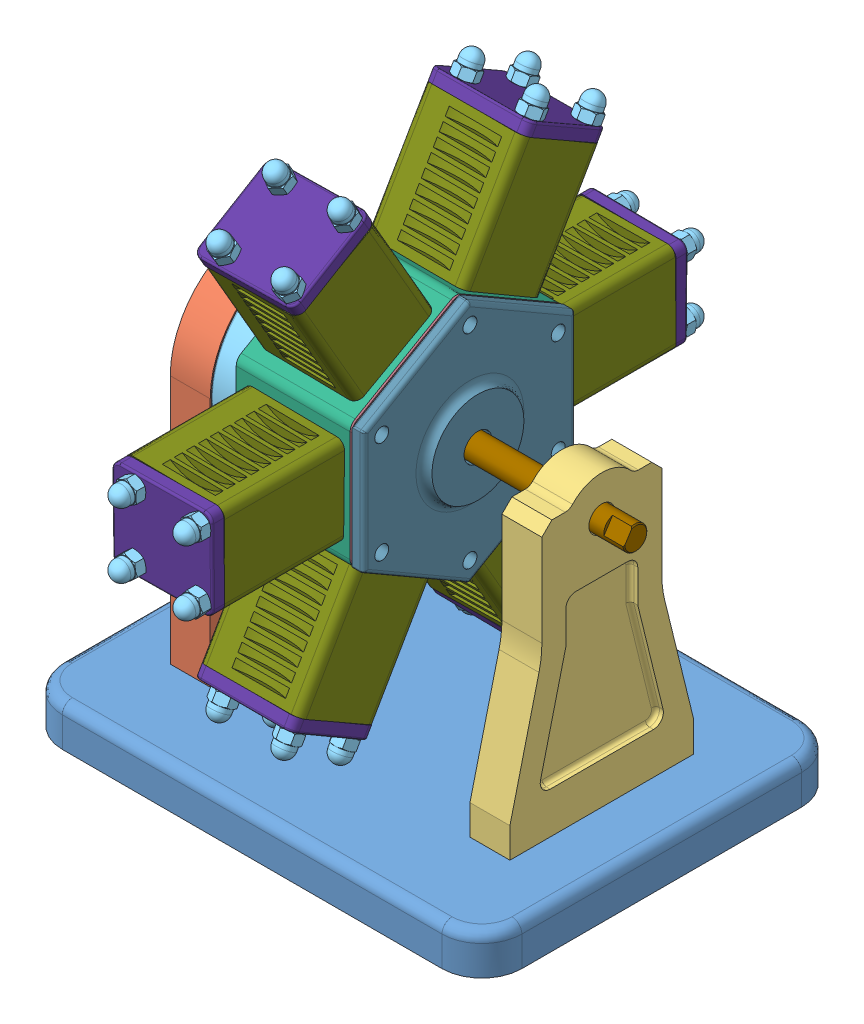
SolidWorks assembly Motor Assembly, configuration Default. Lengths in mm.
Overall size (230 270.19 262).
127 component instances, 25 part files, 104 mates.
Components (placement in the parent):
- 1.Base-1: 1.Base [Default] at (78.8559 86.8104 196.0096) size (230 20 180)
- 2.Pillar Support-1: 2.Pillar Support [Default] at (3.8559 231.8104 196.0096) x (0 0 -1) z (1 0 0) size (92 171 20)
- 3.Bearing Holder-1: 3.Bearing Holder [Default] at (153.8559 231.8104 196.0096) x (0 0 1) z (-1 0 0) size (92 145 20)
- 11.Valve-1: 11.Valve [Default] at (33.8559 233.4481 198.5232) x (0 -0.240272 0.970706) z (-1 0 0) size (42 42 14)
- 12.Valve Housing-1: 12.Valve Housing [Default] at (33.8559 231.8104 196.0096) x (0 0.866025 0.5) z (-1 0 0) size (92 92 30)
- 19.Crankcase-1: 19.Crankcase [Default] at (65.8559 231.8104 196.0096) x (0 0.5 -0.866025) z (1 0 0) size (120.85 106 57)
- Crankshaft Assembly-1: Crankshaft Assembly [Default] at (125.4269 231.5312 143.2681) x (0 -0.837859 0.545886) z (-1 0 0) size (67.26 66 135)
  - 16.Crankshaft Counterweight-1: 16.Crankshaft Counterweight [Default] at (28.5569 44.3424 45.571) size (67.26 66 12)
  - 18.Crankshaft Pin-1: 18.Crankshaft Pin [Default] at (28.5569 62.3424 78.571) size (12 12 38)
  - 16.Crankshaft Counterweight-2: 16.Crankshaft Counterweight [Default] at (28.5569 44.3424 73.571) size (67.26 66 12)
  - 17.Crankshaft-1: 17.Crankshaft [Default] at (28.5569 44.3424 50.571) x (-1 0 0) z (0 0 -1) size (12 12 106)
- 14.Crankshaft Valve-1: 14.Crankshaft Valve [Default] at (56.8559 231.8104 196.0096) x (0 0.837859 -0.545886) z (-1 0 0) size (12 12 33)
- radial ball bearing_68_skf-1: radial ball bearing_68_skf [SKF - 6001 - Full,DE,NC,Full_68] at (153.8559 231.8104 196.0096) x (1 0 0) z (0 -0.041942 0.99912) size (8 28 28)
- radial ball bearing_68_skf-2: radial ball bearing_68_skf [SKF - 6001 - Full,DE,NC,Full_68] at (41.8559 231.8104 196.0096) x (1 0 0) z (0 -0.041942 0.99912) size (8 28 28)
- 15.Connecting Rod Hub-1: 15.Connecting Rod Hub [Default] at (65.8559 241.6363 211.0911) x (0 0.906482 0.422244) z (0 0.422244 -0.906482) size (42 16 42)
- 20.Crankcase Gasket-1: 20.Crankcase Gasket [Default] at (91.8559 231.8104 196.0096) x (0 0 1) z (-1 0 0) size (106 120.85 1)
- 21.Crankcase cover-1: 21.Crankcase cover [Default] at (85.8559 231.8104 196.0096) x (0 0 -1) z (1 0 0) size (106 122.09 16)
- radial ball bearing_68_skf-3: radial ball bearing_68_skf [SKF - 6001 - Full,DE,NC,Full_68] at (89.8559 231.8104 196.0096) x (1 0 0) z (0 0.414709 0.909954) size (8 28 28)
- 22.Hub Pin-1: 22.Hub Pin [Default] at (73.8559 225.6978 212.4921) x (0 0.010581 0.999944) z (-1 0 0) size (5 5 16)
- 22.Hub Pin-2: 22.Hub Pin [Default] at (73.8559 232.4537 197.9884) x (0 -0.14802 0.988984) z (-1 0 0) size (5 5 16)
- 22.Hub Pin-3: 22.Hub Pin [Default] at (73.8559 234.8804 225.5948) x (0 -0.272819 0.962065) z (-1 0 0) size (5 5 16)
- 22.Hub Pin-4: 22.Hub Pin [Default] at (73.8559 250.819 224.1937) x (0 -0.361308 0.932447) z (-1 0 0) size (5 5 16)
- 22.Hub Pin-5: 22.Hub Pin [Default] at (73.8559 257.5749 209.69) x (0 0.989021 0.147773) z (-1 0 0) size (5 5 16)
- 22.Hub Pin-6: 22.Hub Pin [Default] at (73.8559 248.3923 196.5874) x (0 -0.42038 0.907348) z (-1 0 0) size (5 5 16)
- 8.Cylinder-1: 8.Cylinder [Default] at (65.8559 277.7097 169.5096) x (0.99993 0.00593 0.010271) z (0 0.866025 -0.5) size (50 45 62)
- 9.Cylinder Head-1: 9.Cylinder Head [Default] at (65.8559 329.6713 139.5096) x (-0.999937 0.005618 0.00973) z (-0.011235 -0.499968 -0.865971) size (50 8 45)
- 10.Cylinder Bolt-1: 10.Cylinder Bolt [Default] at (82.1193 328.2166 121.57) x (1 0 0) z (0 -0.866025 0.5) size (6 6 82)
- 10.Cylinder Bolt-6: 10.Cylinder Bolt [Default] at (49.5924 328.2166 121.57) x (0.996402 -0.042374 -0.073394) z (0 -0.866025 0.5) size (6 6 82)
- 10.Cylinder Bolt-7: 10.Cylinder Bolt [Default] at (49.5924 344.4801 149.7392) x (0.9776 -0.105236 -0.182274) z (0 -0.866025 0.5) size (6 6 82)
- 10.Cylinder Bolt-8: 10.Cylinder Bolt [Default] at (82.1193 344.4801 149.7392) x (0.928571 -0.185577 -0.321429) z (0 -0.866025 0.5) size (6 6 82)
- 10.Cylinder Bolt-22: 10.Cylinder Bolt [Default] at (82.1193 328.2166 270.4492) x (0.928571 0.185577 -0.321429) z (0 -0.866025 -0.5) size (6 6 82)
- 10.Cylinder Bolt-23: 10.Cylinder Bolt [Default] at (82.1193 215.5469 316.7196) x (0.928571 0.371154 0) z (0 0 -1) size (6 6 82)
- 10.Cylinder Bolt-24: 10.Cylinder Bolt [Default] at (82.1193 119.1407 242.28) x (0.928571 0.185577 0.321429) z (0 0.866025 -0.5) size (6 6 82)
- 10.Cylinder Bolt-25: 10.Cylinder Bolt [Default] at (82.1193 135.4042 121.57) x (0.928571 -0.185577 0.321429) z (0 0.866025 0.5) size (6 6 82)
- 10.Cylinder Bolt-26: 10.Cylinder Bolt [Default] at (82.1193 248.0739 75.2996) x (0.928571 -0.371154 0) z (0 0 1) size (6 6 82)
- 10.Cylinder Bolt-27: 10.Cylinder Bolt [Default] at (49.5924 328.2166 270.4492) x (0.9776 0.105236 -0.182274) z (0 -0.866025 -0.5) size (6 6 82)
- 10.Cylinder Bolt-28: 10.Cylinder Bolt [Default] at (49.5924 215.5469 316.7196) x (0.9776 0.210472 0) z (0 0 -1) size (6 6 82)
- 10.Cylinder Bolt-29: 10.Cylinder Bolt [Default] at (49.5924 119.1407 242.28) x (0.9776 0.105236 0.182274) z (0 0.866025 -0.5) size (6 6 82)
- 10.Cylinder Bolt-30: 10.Cylinder Bolt [Default] at (49.5924 135.4042 121.57) x (0.9776 -0.105236 0.182274) z (0 0.866025 0.5) size (6 6 82)
- 10.Cylinder Bolt-31: 10.Cylinder Bolt [Default] at (49.5924 248.0739 75.2996) x (0.9776 -0.210472 0) z (0 0 1) size (6 6 82)
- 10.Cylinder Bolt-32: 10.Cylinder Bolt [Default] at (49.5924 344.4801 242.28) x (0.996402 0.042374 -0.073394) z (0 -0.866025 -0.5) size (6 6 82)
- 10.Cylinder Bolt-33: 10.Cylinder Bolt [Default] at (49.5924 248.0739 316.7196) x (0.996402 0.084748 0) z (0 0 -1) size (6 6 82)
- 10.Cylinder Bolt-34: 10.Cylinder Bolt [Default] at (49.5924 135.4042 270.4492) x (0.996402 0.042374 0.073394) z (0 0.866025 -0.5) size (6 6 82)
- 10.Cylinder Bolt-35: 10.Cylinder Bolt [Default] at (49.5924 119.1407 149.7392) x (0.996402 -0.042374 0.073394) z (0 0.866025 0.5) size (6 6 82)
- 10.Cylinder Bolt-36: 10.Cylinder Bolt [Default] at (49.5924 215.5469 75.2996) x (0.996402 -0.084748 0) z (0 0 1) size (6 6 82)
- 10.Cylinder Bolt-37: 10.Cylinder Bolt [Default] at (82.1193 344.4801 242.28) x (1 0 0) z (0 -0.866025 -0.5) size (6 6 82)
- 10.Cylinder Bolt-38: 10.Cylinder Bolt [Default] at (82.1193 248.0739 316.7196) x (1 0 0) z (0 0 -1) size (6 6 82)
- 10.Cylinder Bolt-39: 10.Cylinder Bolt [Default] at (82.1193 135.4042 270.4492) x (1 0 0) z (0 0.866025 -0.5) size (6 6 82)
- 10.Cylinder Bolt-40: 10.Cylinder Bolt [Default] at (82.1193 119.1407 149.7392) x (1 0 0) z (0 0.866025 0.5) size (6 6 82)
- 10.Cylinder Bolt-41: 10.Cylinder Bolt [Default] at (82.1193 215.5469 75.2996) size (6 6 82)
- 9.Cylinder Head-5: 9.Cylinder Head [Default] at (65.8559 329.6713 252.5096) x (-0.999937 -0.005618 0.00973) z (-0.011235 0.499968 -0.865971) size (50 8 45)
- 9.Cylinder Head-6: 9.Cylinder Head [Default] at (65.8559 231.8104 309.0096) x (-0.999937 -0.011235 0) z (-0.011235 0.999937 0) size (50 8 45)
- 9.Cylinder Head-7: 9.Cylinder Head [Default] at (65.8559 133.9495 252.5096) x (-0.999937 -0.005618 -0.00973) z (-0.011235 0.499968 0.865971) size (50 8 45)
- 9.Cylinder Head-8: 9.Cylinder Head [Default] at (65.8559 133.9495 139.5096) x (-0.999937 0.005618 -0.00973) z (-0.011235 -0.499968 0.865971) size (50 8 45)
- 9.Cylinder Head-9: 9.Cylinder Head [Default] at (65.8559 231.8104 83.0096) x (-0.999937 0.011235 0) z (-0.011235 -0.999937 0) size (50 8 45)
- 8.Cylinder-5: 8.Cylinder [Default] at (65.8559 277.7097 222.5096) x (0.99993 -0.00593 0.010271) z (0 0.866025 0.5) size (50 45 62)
- 8.Cylinder-6: 8.Cylinder [Default] at (65.8559 231.8104 249.0096) x (0.99993 -0.01186 0) z (0 0 1) size (50 45 62)
- 8.Cylinder-7: 8.Cylinder [Default] at (65.8559 185.9111 222.5096) x (0.99993 -0.00593 -0.010271) z (0 -0.866025 0.5) size (50 45 62)
- 8.Cylinder-8: 8.Cylinder [Default] at (65.8559 185.9111 169.5096) x (0.99993 0.00593 -0.010271) z (0 -0.866025 -0.5) size (50 45 62)
- 8.Cylinder-9: 8.Cylinder [Default] at (65.8559 231.8104 143.0096) x (0.99993 0.01186 0) z (0 0 -1) size (50 45 62)
- Piston Assembly-1: Piston Assembly [Default] at (41.1019 276.0191 173.3163) x (0 -0.5 -0.866025) z (1 0 0) size (35.7 32 35.67)
  - 4.Piston-1: 4.Piston [Default] at (2.4514 23.7914 24.754) size (32 32 32)
  - 5.Piston_Pin-1: 5.Piston_Pin [Default] at (2.4514 23.7914 9.754) size (5 5 30)
  - 7.Piston Compression Ring-1: 7.Piston Compression Ring [Default] at (2.4514 34.0414 24.754) x (0.992378 0 0.12323) z (-0.12323 0 0.992378) size (32 1.5 31.97)
  - 7.Piston Compression Ring-2: 7.Piston Compression Ring [Default] at (2.4514 29.5414 24.754) x (0.99851 0 0.05457) z (-0.05457 0 0.99851) size (32 1.5 31.97)
- 6.Connecting_rod-1: 6.Connecting_rod [Default] at (65.8559 295.3973 159.2977) x (0 -0.783418 0.621495) z (1 0 0) size (70 10 10)
- domed cap nut_din-1: domed cap nut_din [DIN 1587 - M6 --NNU] at (49.5924 326.7357 122.425) x (0 0.866025 -0.5) z (-0.5 0.433013 0.75) size (12 11.55 10)
- domed cap nut_din-6: domed cap nut_din [DIN 1587 - M6 --NNU] at (82.1193 326.7357 122.425) x (0 0.866025 -0.5) z (-0.424807 0.452642 0.783999) size (12 11.55 10)
- domed cap nut_din-7: domed cap nut_din [DIN 1587 - M6 --NNU] at (49.5924 342.9992 150.5942) x (0 0.866025 -0.5) z (-0.306526 0.475931 0.824337) size (12 11.55 10)
- domed cap nut_din-8: domed cap nut_din [DIN 1587 - M6 --NNU] at (82.1193 342.9992 150.5942) x (0 0.866025 -0.5) z (-0.142857 0.494872 0.857143) size (12 11.55 10)
- domed cap nut_din-10: domed cap nut_din [DIN 1587 - M6 --NNU] at (49.5924 326.7357 269.5942) x (0 0.866025 0.5) z (-0.306526 -0.475931 0.824337) size (12 11.55 10)
- domed cap nut_din-11: domed cap nut_din [DIN 1587 - M6 --NNU] at (49.5924 215.5469 315.0096) x (0 0 1) z (-0.306526 -0.951862 0) size (12 11.55 10)
- domed cap nut_din-12: domed cap nut_din [DIN 1587 - M6 --NNU] at (49.5924 120.6216 241.425) x (0 -0.866025 0.5) z (-0.306526 -0.475931 -0.824337) size (12 11.55 10)
- domed cap nut_din-13: domed cap nut_din [DIN 1587 - M6 --NNU] at (49.5924 136.8851 122.425) x (0 -0.866025 -0.5) z (-0.306526 0.475931 -0.824337) size (12 11.55 10)
- domed cap nut_din-14: domed cap nut_din [DIN 1587 - M6 --NNU] at (49.5924 248.0739 77.0096) x (0 0 -1) z (-0.306526 0.951862 0) size (12 11.55 10)
- domed cap nut_din-15: domed cap nut_din [DIN 1587 - M6 --NNU] at (82.1193 326.7357 269.5942) x (0 0.866025 0.5) z (-0.142857 -0.494872 0.857143) size (12 11.55 10)
- domed cap nut_din-16: domed cap nut_din [DIN 1587 - M6 --NNU] at (82.1193 215.5469 315.0096) x (0 0 1) z (-0.142857 -0.989743 0) size (12 11.55 10)
- domed cap nut_din-17: domed cap nut_din [DIN 1587 - M6 --NNU] at (82.1193 120.6216 241.425) x (0 -0.866025 0.5) z (-0.142857 -0.494872 -0.857143) size (12 11.55 10)
- domed cap nut_din-18: domed cap nut_din [DIN 1587 - M6 --NNU] at (82.1193 136.8851 122.425) x (0 -0.866025 -0.5) z (-0.142857 0.494872 -0.857143) size (12 11.55 10)
- domed cap nut_din-19: domed cap nut_din [DIN 1587 - M6 --NNU] at (82.1193 248.0739 77.0096) x (0 0 -1) z (-0.142857 0.989743 0) size (12 11.55 10)
- domed cap nut_din-20: domed cap nut_din [DIN 1587 - M6 --NNU] at (82.1193 342.9992 241.425) x (0 0.866025 0.5) z (-0.424807 -0.452642 0.783999) size (12 11.55 10)
- domed cap nut_din-21: domed cap nut_din [DIN 1587 - M6 --NNU] at (82.1193 248.0739 315.0096) x (0 0 1) z (-0.424807 -0.905284 0) size (12 11.55 10)
- domed cap nut_din-22: domed cap nut_din [DIN 1587 - M6 --NNU] at (82.1193 136.8851 269.5942) x (0 -0.866025 0.5) z (-0.424807 -0.452642 -0.783999) size (12 11.55 10)
- domed cap nut_din-23: domed cap nut_din [DIN 1587 - M6 --NNU] at (82.1193 120.6216 150.5942) x (0 -0.866025 -0.5) z (-0.424807 0.452642 -0.783999) size (12 11.55 10)
- domed cap nut_din-24: domed cap nut_din [DIN 1587 - M6 --NNU] at (82.1193 215.5469 77.0096) x (0 0 -1) z (-0.424807 0.905284 0) size (12 11.55 10)
- domed cap nut_din-25: domed cap nut_din [DIN 1587 - M6 --NNU] at (49.5924 342.9992 241.425) x (0 0.866025 0.5) z (-0.5 -0.433013 0.75) size (12 11.55 10)
- domed cap nut_din-26: domed cap nut_din [DIN 1587 - M6 --NNU] at (49.5924 248.0739 315.0096) x (0 0 1) z (-0.5 -0.866025 0) size (12 11.55 10)
- domed cap nut_din-27: domed cap nut_din [DIN 1587 - M6 --NNU] at (49.5924 136.8851 269.5942) x (0 -0.866025 0.5) z (-0.5 -0.433013 -0.75) size (12 11.55 10)
- domed cap nut_din-28: domed cap nut_din [DIN 1587 - M6 --NNU] at (49.5924 120.6216 150.5942) x (0 -0.866025 -0.5) z (-0.5 0.433013 -0.75) size (12 11.55 10)
- domed cap nut_din-29: domed cap nut_din [DIN 1587 - M6 --NNU] at (49.5924 215.5469 77.0096) x (0 0 -1) z (-0.5 0.866025 0) size (12 11.55 10)
- Piston Assembly-4: Piston Assembly [Default] at (41.1019 287.1817 230.8088) x (0 0.5 -0.866025) z (1 0 0) size (35.7 32 35.67)
  - 4.Piston-1: 4.Piston [Default] at (2.4514 23.7914 24.754) size (32 32 32)
  - 5.Piston_Pin-1: 5.Piston_Pin [Default] at (2.4514 23.7914 9.754) size (5 5 30)
  - 7.Piston Compression Ring-1: 7.Piston Compression Ring [Default] at (2.4514 34.0414 24.754) x (0.992378 0 0.12323) z (-0.12323 0 0.992378) size (32 1.5 31.97)
  - 7.Piston Compression Ring-2: 7.Piston Compression Ring [Default] at (2.4514 29.5414 24.754) x (0.99851 0 0.05457) z (-0.05457 0 0.99851) size (32 1.5 31.97)
- 6.Connecting_rod-4: 6.Connecting_rod [Default] at (65.8559 309.0114 240.5816) x (0 -0.857274 -0.51486) z (1 0 0) size (70 10 10)
- Piston Assembly-6: Piston Assembly [Default] at (41.1019 229.359 114.2005) x (0 1 0) z (1 0 0) size (35.7 32 35.67)
  - 4.Piston-1: 4.Piston [Default] at (2.4514 23.7914 24.754) size (32 32 32)
  - 5.Piston_Pin-1: 5.Piston_Pin [Default] at (2.4514 23.7914 9.754) size (5 5 30)
  - 7.Piston Compression Ring-1: 7.Piston Compression Ring [Default] at (2.4514 34.0414 24.754) x (0.992378 0 0.12323) z (-0.12323 0 0.992378) size (32 1.5 31.97)
  - 7.Piston Compression Ring-2: 7.Piston Compression Ring [Default] at (2.4514 29.5414 24.754) x (0.99851 0 0.05457) z (-0.05457 0 0.99851) size (32 1.5 31.97)
- 6.Connecting_rod-6: 6.Connecting_rod [Default] at (65.8559 231.8104 137.9919) x (0 0.010722 0.999943) z (1 0 0) size (70 10 10)
- Piston Assembly-8: Piston Assembly [Default] at (41.1019 162.7867 158.9894) x (0 0.5 -0.866025) z (1 0 0) size (35.7 32 35.67)
  - 4.Piston-1: 4.Piston [Default] at (2.4514 23.7914 24.754) size (32 32 32)
  - 5.Piston_Pin-1: 5.Piston_Pin [Default] at (2.4514 23.7914 9.754) size (5 5 30)
  - 7.Piston Compression Ring-1: 7.Piston Compression Ring [Default] at (2.4514 34.0414 24.754) x (0.992378 0 0.12323) z (-0.12323 0 0.992378) size (32 1.5 31.97)
  - 7.Piston Compression Ring-2: 7.Piston Compression Ring [Default] at (2.4514 29.5414 24.754) x (0.99851 0 0.05457) z (-0.05457 0 0.99851) size (32 1.5 31.97)
- 6.Connecting_rod-8: 6.Connecting_rod [Default] at (65.8559 184.6164 168.7621) x (0 0.684691 0.728834) z (1 0 0) size (70 10 10)
- Piston Assembly-10: Piston Assembly [Default] at (41.1019 194.3459 214.8092) x (0 0.5 0.866025) z (1 0 0) size (35.7 32 35.67)
  - 4.Piston-1: 4.Piston [Default] at (2.4514 23.7914 24.754) size (32 32 32)
  - 5.Piston_Pin-1: 5.Piston_Pin [Default] at (2.4514 23.7914 9.754) size (5 5 30)
  - 7.Piston Compression Ring-1: 7.Piston Compression Ring [Default] at (2.4514 34.0414 24.754) x (0.992378 0 0.12323) z (-0.12323 0 0.992378) size (32 1.5 31.97)
  - 7.Piston Compression Ring-2: 7.Piston Compression Ring [Default] at (2.4514 29.5414 24.754) x (0.99851 0 0.05457) z (-0.05457 0 0.99851) size (32 1.5 31.97)
- 6.Connecting_rod-10: 6.Connecting_rod [Default] at (65.8559 174.9676 228.8278) x (0 0.998547 -0.053884) z (1 0 0) size (70 10 10)
- Piston Assembly-13: Piston Assembly [Default] at (90.6099 234.2618 257.3117) x (0 -1 0) z (-1 0 0) size (35.7 32 35.67)
  - 4.Piston-1: 4.Piston [Default] at (2.4514 23.7914 24.754) size (32 32 32)
  - 5.Piston_Pin-1: 5.Piston_Pin [Default] at (2.4514 23.7914 9.754) size (5 5 30)
  - 7.Piston Compression Ring-1: 7.Piston Compression Ring [Default] at (2.4514 34.0414 24.754) x (0.992378 0 0.12323) z (-0.12323 0 0.992378) size (32 1.5 31.97)
  - 7.Piston Compression Ring-2: 7.Piston Compression Ring [Default] at (2.4514 29.5414 24.754) x (0.99851 0 0.05457) z (-0.05457 0 0.99851) size (32 1.5 31.97)
- 6.Connecting_rod-13: 6.Connecting_rod [Default] at (65.8559 231.8104 281.1031) x (0 0.31681 -0.948489) z (-1 0 0) size (70 10 10)
- socket head cap screw_iso-2: socket head cap screw_iso [ISO 4762 M6 x 45 - 45N] at (-6.1441 270.8104 196.0096) size (51 10 10)
- socket head cap screw_iso-3: socket head cap screw_iso [ISO 4762 M6 x 45 - 45N] at (-6.1441 251.3104 229.7846) size (51 10 10)
- socket head cap screw_iso-4: socket head cap screw_iso [ISO 4762 M6 x 45 - 45N] at (-6.1441 212.3104 229.7846) size (51 10 10)
- socket head cap screw_iso-5: socket head cap screw_iso [ISO 4762 M6 x 45 - 45N] at (-6.1441 192.8104 196.0096) size (51 10 10)
- socket head cap screw_iso-6: socket head cap screw_iso [ISO 4762 M6 x 45 - 45N] at (-6.1441 212.3104 162.2346) size (51 10 10)
- socket head cap screw_iso-7: socket head cap screw_iso [ISO 4762 M6 x 45 - 45N] at (-6.1441 251.3104 162.2346) size (51 10 10)
- 13.Flywheel-1: 13.Flywheel [Default] at (125.8559 231.8104 196.0096) x (0 -0.945721 0.324979) z (-1 0 0) size (160 160 36) (hidden)
Mates (geometry in assembly coordinates):
- Coincident1: coincident anti-aligned: plane of 1.Base-1 through (-16.1441 106.8104 266.0096) normal (0 1 0); plane of 2.Pillar Support-1 through (13.8559 106.8104 242.0096) normal (0 -1 0)
- Concentric3: concentric anti-aligned: circle of 1.Base-1; circle of 2.Pillar Support-1
- Concentric4: concentric anti-aligned: circle of 1.Base-1; circle of 2.Pillar Support-1
- Concentric5: concentric anti-aligned: circle of 1.Base-1; circle of 3.Bearing Holder-1
- Concentric6: concentric aligned: circle of 1.Base-1; circle of 3.Bearing Holder-1
- Coincident2: coincident anti-aligned: plane of 1.Base-1 through (-16.1441 106.8104 266.0096) normal (0 1 0); plane of 3.Bearing Holder-1 through (143.8559 106.8104 150.0096) normal (0 -1 0)
- Concentric7: concentric aligned: cylinder of 2.Pillar Support-1 through (3.8559 231.8104 196.0096) axis (1 0 0) radius 12.5; cylinder of 12.Valve Housing-1 through (3.8559 231.8104 196.0096) axis (1 0 0) radius 12
- Coincident3: coincident anti-aligned: circle of 2.Pillar Support-1; circle of 12.Valve Housing-1
- Coincident4: coincident anti-aligned: plane of 11.Valve-1 through (19.8559 234.2246 197.7905) normal (-1 0 0); plane of 12.Valve Housing-1 through (19.8559 231.8104 196.0096) normal (1 0 0)
- Parallel1: parallel aligned: plane of 1.Base-1 through (-16.1441 106.8104 286.0096) normal (0 0 1); plane of 19.Crankcase-1 through (33.8559 259.5232 249.0096) normal (0 0 1)
- Concentric11: concentric aligned: circle of 3.Bearing Holder-1; circle of 19.Crankcase-1
- Concentric12: concentric anti-aligned: cylinder of 3.Bearing Holder-1 through (143.8559 231.8104 196.0096) axis (1 0 0) radius 6.5; cylinder of Crankshaft Assembly-1/17.Crankshaft-1 through (180.8559 231.8104 196.0096) axis (-1 0 0) radius 6
- Concentric13: concentric aligned: cylinder of Crankshaft Assembly-1/16.Crankshaft Counterweight-2 through (46.8559 231.8104 196.0096) axis (1 0 0) radius 6; cylinder of 14.Crankshaft Valve-1 through (33.8559 231.8104 196.0096) axis (1 0 0) radius 6
- Concentric14: concentric aligned: cylinder of Crankshaft Assembly-1/16.Crankshaft Counterweight-2 through (51.8559 211.8456 223.0746) axis (0 0.593626 -0.804741) radius 1.5; cylinder of 14.Crankshaft Valve-1 through (51.8559 228.2486 200.838) axis (0 0.593626 -0.804741) radius 1.5
- Concentric16: concentric aligned: cylinder of 11.Valve-1 through (19.8559 234.2246 197.7905) axis (1 0 0) radius 2; cylinder of 14.Crankshaft Valve-1 through (23.8559 234.2246 197.7905) axis (1 0 0) radius 2
- Coincident7: coincident anti-aligned: plane of 11.Valve-1 through (33.8559 234.2246 197.7905) normal (1 0 0); plane of 14.Crankshaft Valve-1 through (33.8559 231.8104 196.0096) normal (-1 0 0)
- Coincident9: coincident anti-aligned: plane of 12.Valve Housing-1 through (33.8559 231.8104 196.0096) normal (1 0 0); plane of 19.Crankcase-1 through (33.8559 204.0976 244.0096) normal (-1 0 0)
- Concentric17: concentric anti-aligned: cylinder of Crankshaft Assembly-1/17.Crankshaft-1 through (180.8559 231.8104 196.0096) axis (-1 0 0) radius 6; cylinder of radial ball bearing_68_skf-1 through (133.2184 231.8104 196.0096) axis (1 0 0) radius 6
- Concentric18: concentric anti-aligned: cylinder of 3.Bearing Holder-1 through (157.8559 231.8104 196.0096) axis (-1 0 0) radius 14; cylinder of radial ball bearing_68_skf-1 through (133.2184 231.8104 196.0096) axis (1 0 0) radius 14
- Coincident10: coincident anti-aligned: plane of 3.Bearing Holder-1 through (157.8559 231.8104 196.0096) normal (-1 0 0); plane of radial ball bearing_68_skf-1 through (157.8559 245.4983 196.5842) normal (1 0 0)
- Concentric19: concentric anti-aligned: cylinder of Crankshaft Assembly-1/17.Crankshaft-1 through (180.8559 231.8104 196.0096) axis (-1 0 0) radius 6; cylinder of radial ball bearing_68_skf-2 through (21.2184 231.8104 196.0096) axis (1 0 0) radius 6
- Coincident11: coincident anti-aligned: plane of 19.Crankcase-1 through (37.8559 231.8104 196.0096) normal (1 0 0); plane of radial ball bearing_68_skf-2 through (37.8559 243.4002 196.4961) normal (-1 0 0)
- Concentric20: concentric anti-aligned: cylinder of Crankshaft Assembly-1/18.Crankshaft Pin-1 through (84.8559 246.2957 206.6949) axis (-1 0 0) radius 6; cylinder of 15.Connecting Rod Hub-1 through (105.541 246.2957 206.6949) axis (1 0 0) radius 6
- Coincident13: coincident anti-aligned: plane of Crankshaft Assembly-1/16.Crankshaft Counterweight-2 through (57.8559 246.2957 206.6949) normal (1 0 0); plane of 15.Connecting Rod Hub-1 through (57.8559 240.8568 204.1614) normal (-1 0 0)
- Coincident14: coincident anti-aligned: plane of 19.Crankcase-1 through (90.8559 204.0976 244.0096) normal (1 0 0); plane of 20.Crankcase Gasket-1 through (90.8559 204.0976 148.0096) normal (-1 0 0)
- Concentric21: concentric anti-aligned: circle of 19.Crankcase-1; circle of 20.Crankcase Gasket-1
- Concentric22: concentric anti-aligned: cylinder of 21.Crankcase cover-1 through (91.8559 231.8104 196.0096) axis (-1 0 0) radius 14; cylinder of radial ball bearing_68_skf-3 through (69.2184 231.8104 196.0096) axis (1 0 0) radius 14
- Concentric23: concentric anti-aligned: cylinder of Crankshaft Assembly-1/17.Crankshaft-1 through (180.8559 231.8104 196.0096) axis (-1 0 0) radius 6; cylinder of radial ball bearing_68_skf-3 through (69.2184 231.8104 196.0096) axis (1 0 0) radius 6
- Coincident16: coincident anti-aligned: plane of 20.Crankcase Gasket-1 through (91.8559 204.0976 148.0096) normal (1 0 0); plane of 21.Crankcase cover-1 through (91.8559 231.8104 196.0096) normal (-1 0 0)
- Concentric24: concentric anti-aligned: cylinder of 15.Connecting Rod Hub-1 through (73.8559 230.3572 208.0959) axis (-1 0 0) radius 2.5; cylinder of 22.Hub Pin-1 through (57.8559 230.3572 208.0959) axis (1 0 0) radius 2.5
- Coincident17: coincident aligned: plane of 15.Connecting Rod Hub-1 through (73.8559 227.2596 197.8277) normal (1 0 0); plane of 22.Hub Pin-1 through (73.8559 230.3572 208.0959) normal (1 0 0)
- Coincident18: coincident aligned: plane of 15.Connecting Rod Hub-1 through (73.8559 227.2596 197.8277) normal (1 0 0); plane of 22.Hub Pin-2 through (73.8559 237.1131 193.5922) normal (1 0 0)
- Concentric27: concentric anti-aligned: cylinder of 15.Connecting Rod Hub-1 through (73.8559 237.1131 193.5922) axis (-1 0 0) radius 2.5; cylinder of 22.Hub Pin-2 through (57.8559 237.1131 193.5922) axis (1 0 0) radius 2.5
- Coincident19: coincident aligned: plane of 15.Connecting Rod Hub-1 through (73.8559 227.2596 197.8277) normal (1 0 0); plane of 22.Hub Pin-3 through (73.8559 239.5398 221.1986) normal (1 0 0)
- Concentric28: concentric anti-aligned: cylinder of 15.Connecting Rod Hub-1 through (73.8559 239.5398 221.1986) axis (-1 0 0) radius 2.5; cylinder of 22.Hub Pin-3 through (57.8559 239.5398 221.1986) axis (1 0 0) radius 2.5
- Coincident20: coincident aligned: plane of 15.Connecting Rod Hub-1 through (73.8559 227.2596 197.8277) normal (1 0 0); plane of 22.Hub Pin-4 through (73.8559 255.4784 219.7975) normal (1 0 0)
- Concentric29: concentric anti-aligned: cylinder of 15.Connecting Rod Hub-1 through (73.8559 255.4784 219.7975) axis (-1 0 0) radius 2.5; cylinder of 22.Hub Pin-4 through (57.8559 255.4784 219.7975) axis (1 0 0) radius 2.5
- Coincident21: coincident aligned: plane of 15.Connecting Rod Hub-1 through (73.8559 227.2596 197.8277) normal (1 0 0); plane of 22.Hub Pin-5 through (73.8559 262.2343 205.2938) normal (1 0 0)
- Concentric30: concentric anti-aligned: cylinder of 15.Connecting Rod Hub-1 through (73.8559 262.2343 205.2938) axis (-1 0 0) radius 2.5; cylinder of 22.Hub Pin-5 through (57.8559 262.2343 205.2938) axis (1 0 0) radius 2.5
- Coincident22: coincident aligned: plane of 15.Connecting Rod Hub-1 through (73.8559 227.2596 197.8277) normal (1 0 0); plane of 22.Hub Pin-6 through (73.8559 253.0516 192.1912) normal (1 0 0)
- Concentric31: concentric anti-aligned: cylinder of 15.Connecting Rod Hub-1 through (73.8559 253.0516 192.1912) axis (-1 0 0) radius 2.5; cylinder of 22.Hub Pin-6 through (57.8559 253.0516 192.1912) axis (1 0 0) radius 2.5
- Concentric32: concentric anti-aligned: circle of 19.Crankcase-1; circle of 8.Cylinder-1
- Concentric33: concentric aligned: circle of 19.Crankcase-1; circle of 8.Cylinder-1
- Coincident25: coincident anti-aligned: plane of 19.Crankcase-1 through (33.8559 263.8533 145.5096) normal (0 0.866025 -0.5); plane of 8.Cylinder-1 through (41.6382 286.8168 185.2835) normal (0 -0.866025 0.5)
- Concentric34: concentric anti-aligned: cylinder of 8.Cylinder-1 through (65.8559 329.6713 139.5096) axis (0 -0.866025 0.5) radius 16; cylinder of 9.Cylinder Head-1 through (65.8559 327.9392 140.5096) axis (0 0.866025 -0.5) radius 16
- Concentric35: concentric aligned: circle of 8.Cylinder-1; circle of 9.Cylinder Head-1
- Concentric36: concentric anti-aligned: cylinder of 8.Cylinder-1 through (82.1193 321.5395 125.425) axis (0 -0.866025 0.5) radius 3.5; cylinder of 10.Cylinder Bolt-1 through (82.1193 257.2025 162.57) axis (0 0.866025 -0.5) radius 3
- Distance1: distance = 7.71 mm aligned: plane of 10.Cylinder Bolt-1 through (82.1193 328.2166 121.57) normal (0 0.866025 -0.5); plane of 8.Cylinder-1 through (41.6382 338.7783 155.2835) normal (0 0.866025 -0.5)
- Concentric40: concentric anti-aligned: cylinder of 8.Cylinder-1 through (49.5924 321.5395 125.425) axis (0 -0.866025 0.5) radius 3.5; cylinder of 10.Cylinder Bolt-6 through (49.5924 257.2025 162.57) axis (0 0.866025 -0.5) radius 3
- Distance6: distance = 7.71 mm aligned: plane of 10.Cylinder Bolt-6 through (49.5924 328.2166 121.57) normal (0 0.866025 -0.5); plane of 8.Cylinder-1 through (41.6382 338.7783 155.2835) normal (0 0.866025 -0.5)
- Distance7: distance = 7.71 mm aligned: plane of 10.Cylinder Bolt-7 through (49.5924 344.4801 149.7392) normal (0 0.866025 -0.5); plane of 8.Cylinder-1 through (41.6382 338.7783 155.2835) normal (0 0.866025 -0.5)
- Concentric41: concentric anti-aligned: cylinder of 8.Cylinder-1 through (49.5924 337.803 153.5942) axis (0 -0.866025 0.5) radius 3.5; cylinder of 10.Cylinder Bolt-7 through (49.5924 273.466 190.7392) axis (0 0.866025 -0.5) radius 3
- Distance8: distance = 7.71 mm aligned: plane of 10.Cylinder Bolt-8 through (82.1193 344.4801 149.7392) normal (0 0.866025 -0.5); plane of 8.Cylinder-1 through (41.6382 338.7783 155.2835) normal (0 0.866025 -0.5)
- Concentric42: concentric anti-aligned: cylinder of 8.Cylinder-1 through (82.1193 337.803 153.5942) axis (0 -0.866025 0.5) radius 3.5; cylinder of 10.Cylinder Bolt-8 through (82.1193 273.466 190.7392) axis (0 0.866025 -0.5) radius 3
- Coincident27: coincident anti-aligned: plane of 8.Cylinder-1 through (41.6382 338.7783 155.2835) normal (0 0.866025 -0.5); plane of 9.Cylinder Head-1 through (65.8559 329.6713 139.5096) normal (0 -0.866025 0.5)
- Concentric65: concentric aligned: circle of Piston Assembly-1/5.Piston_Pin-1; circle of 6.Connecting_rod-1
- Symmetric1: symmetric aligned: plane of Piston Assembly-1 through (65.8559 281.5905 170.0996) normal (1 0 0); plane of 6.Connecting_rod-1 through (70.8559 300.9688 156.081) normal (1 0 0); plane of 6.Connecting_rod-1 through (60.8559 300.9688 156.081) normal (-1 0 0)
- Coincident33: coincident anti-aligned: plane of Crankshaft Assembly-1/16.Crankshaft Counterweight-1 through (85.8559 246.2957 206.6949) normal (1 0 0); plane of radial ball bearing_68_skf-3 through (85.8559 242.3659 191.199) normal (-1 0 0)
- Concentric68: concentric anti-aligned: cylinder of 8.Cylinder-1 through (65.8559 329.6713 139.5096) axis (0 -0.866025 0.5) radius 16; cylinder of Piston Assembly-1/4.Piston-1 through (65.8559 314.8252 148.081) axis (0 0.866025 -0.5) radius 16
- Concentric69: concentric anti-aligned: cylinder of 22.Hub Pin-6 through (57.8559 253.0516 192.1912) axis (1 0 0) radius 2.5; cylinder of 6.Connecting_rod-1 through (70.8559 253.0516 192.1912) axis (-1 0 0) radius 2.5
- RackPinionMate1: rack pinion = 12 mm: cylinder of Crankshaft Assembly-1/17.Crankshaft-1 through (180.8559 231.8104 196.0096) axis (-1 0 0) radius 6; cylinder of 15.Connecting Rod Hub-1 through (105.541 246.2957 206.6949) axis (1 0 0) radius 6
- Coincident39: coincident anti-aligned: plane of 9.Cylinder Head-1 through (65.8559 334.8674 136.5096) normal (0 0.866025 -0.5); plane of domed cap nut_din-1 through (44.5924 331.0658 129.925) normal (0 -0.866025 0.5)
- Concentric74: concentric anti-aligned: circle of 10.Cylinder Bolt-6; circle of domed cap nut_din-1
- Coincident40: coincident anti-aligned: plane of 9.Cylinder Head-1 through (65.8559 334.8674 136.5096) normal (0 0.866025 -0.5); plane of domed cap nut_din-6 through (77.8713 331.2621 130.265) normal (0 -0.866025 0.5)
- Concentric75: concentric anti-aligned: circle of 10.Cylinder Bolt-1; circle of domed cap nut_din-6
- Coincident41: coincident anti-aligned: plane of 9.Cylinder Head-1 through (65.8559 334.8674 136.5096) normal (0 0.866025 -0.5); plane of domed cap nut_din-7 through (46.5272 347.7585 158.8375) normal (0 -0.866025 0.5)
- Concentric76: concentric anti-aligned: circle of 10.Cylinder Bolt-7; circle of domed cap nut_din-7
- Coincident42: coincident anti-aligned: plane of 9.Cylinder Head-1 through (65.8559 334.8674 136.5096) normal (0 0.866025 -0.5); plane of domed cap nut_din-8 through (80.6908 347.9479 159.1656) normal (0 -0.866025 0.5)
- Concentric77: concentric anti-aligned: circle of 10.Cylinder Bolt-8; circle of domed cap nut_din-8
- Concentric83: concentric aligned: circle of Piston Assembly-4/5.Piston_Pin-1; circle of 6.Connecting_rod-4
- Symmetric4: symmetric aligned: plane of Piston Assembly-4 through (65.8559 288.4079 231.5168) normal (1 0 0); plane of 6.Connecting_rod-4 through (70.8559 310.2375 241.2895) normal (1 0 0); plane of 6.Connecting_rod-4 through (60.8559 310.2375 241.2895) normal (-1 0 0)
- Concentric84: concentric anti-aligned: cylinder of 8.Cylinder-5 through (65.8559 329.6713 252.5096) axis (0 -0.866025 -0.5) radius 16; cylinder of Piston Assembly-4/4.Piston-1 through (65.8559 324.0939 249.2895) axis (0 0.866025 0.5) radius 16
- Concentric85: concentric anti-aligned: cylinder of 22.Hub Pin-5 through (57.8559 262.2343 205.2938) axis (1 0 0) radius 2.5; cylinder of 6.Connecting_rod-4 through (70.8559 262.2343 205.2938) axis (-1 0 0) radius 2.5
- Concentric87: concentric aligned: circle of Piston Assembly-6/5.Piston_Pin-1; circle of 6.Connecting_rod-6
- Symmetric6: symmetric aligned: plane of Piston Assembly-6 through (65.8559 229.359 110.0356) normal (1 0 0); plane of 6.Connecting_rod-6 through (70.8559 231.8104 133.827) normal (1 0 0); plane of 6.Connecting_rod-6 through (60.8559 231.8104 133.827) normal (-1 0 0)
- Concentric88: concentric anti-aligned: cylinder of 8.Cylinder-6 through (65.8559 231.8104 309.0096) axis (0 0 -1) radius 16; cylinder of Piston Assembly-6/4.Piston-1 through (65.8559 231.8104 149.827) axis (0 0 1) radius 16
- Concentric90: concentric anti-aligned: cylinder of 22.Hub Pin-2 through (57.8559 237.1131 193.5922) axis (1 0 0) radius 2.5; cylinder of 6.Connecting_rod-6 through (70.8559 237.1131 193.5922) axis (-1 0 0) radius 2.5
- Concentric92: concentric aligned: circle of Piston Assembly-8/5.Piston_Pin-1; circle of 6.Connecting_rod-8
- Symmetric8: symmetric aligned: plane of Piston Assembly-8 through (65.8559 163.0751 159.1559) normal (1 0 0); plane of 6.Connecting_rod-8 through (70.8559 184.9048 168.9286) normal (1 0 0); plane of 6.Connecting_rod-8 through (60.8559 184.9048 168.9286) normal (-1 0 0)
- Concentric94: concentric anti-aligned: cylinder of 22.Hub Pin-1 through (57.8559 230.3572 208.0959) axis (1 0 0) radius 2.5; cylinder of 6.Connecting_rod-8 through (70.8559 230.3572 208.0959) axis (-1 0 0) radius 2.5
- Concentric96: concentric aligned: circle of 8.Cylinder-8; cylinder of Piston Assembly-8/4.Piston-1 through (65.8559 198.7612 176.9286) axis (0 0.866025 0.5) radius 16
- Concentric98: concentric aligned: circle of Piston Assembly-10/5.Piston_Pin-1; circle of 6.Connecting_rod-10
- Symmetric10: symmetric aligned: plane of Piston Assembly-10 through (65.8559 199.1165 212.0549) normal (1 0 0); plane of 6.Connecting_rod-10 through (70.8559 179.7382 226.0735) normal (1 0 0); plane of 6.Connecting_rod-10 through (60.8559 179.7382 226.0735) normal (-1 0 0)
- Concentric99: concentric anti-aligned: cylinder of 8.Cylinder-7 through (65.8559 133.9495 252.5096) axis (0 0.866025 -0.5) radius 16; cylinder of Piston Assembly-10/4.Piston-1 through (65.8559 165.8818 234.0735) axis (0 -0.866025 0.5) radius 16
- Concentric100: concentric anti-aligned: cylinder of 22.Hub Pin-3 through (57.8559 239.5398 221.1986) axis (1 0 0) radius 2.5; cylinder of 6.Connecting_rod-10 through (70.8559 239.5398 221.1986) axis (-1 0 0) radius 2.5
- Concentric105: concentric aligned: circle of Piston Assembly-13/5.Piston_Pin-1; circle of 6.Connecting_rod-13
- Symmetric13: symmetric aligned: plane of Piston Assembly-13 through (65.8559 234.2618 251.1408) normal (-1 0 0); plane of 6.Connecting_rod-13 through (60.8559 231.8104 274.9322) normal (-1 0 0); plane of 6.Connecting_rod-13 through (70.8559 231.8104 274.9322) normal (1 0 0)
- Concentric106: concentric anti-aligned: cylinder of 8.Cylinder-6 through (65.8559 231.8104 309.0096) axis (0 0 -1) radius 16; cylinder of Piston Assembly-13/4.Piston-1 through (65.8559 231.8104 290.9322) axis (0 0 1) radius 16
- Concentric109: concentric anti-aligned: cylinder of 2.Pillar Support-1 through (-6.1441 270.8104 196.0096) axis (1 0 0) radius 3.5; cylinder of socket head cap screw_iso-2 through (-37.8941 270.8104 196.0096) axis (-1 0 0) radius 5
- Coincident44: coincident anti-aligned: plane of 2.Pillar Support-1 through (-0.1441 270.8104 196.0096) normal (-1 0 0); plane of socket head cap screw_iso-2 through (-0.1441 275.8104 196.0096) normal (1 0 0)
- Concentric110: concentric aligned: cylinder of 2.Pillar Support-1 through (-0.1441 251.3104 229.7846) axis (-1 0 0) radius 6; cylinder of socket head cap screw_iso-3 through (-37.8941 251.3104 229.7846) axis (-1 0 0) radius 5
- Coincident45: coincident anti-aligned: plane of 2.Pillar Support-1 through (-0.1441 251.3104 229.7846) normal (-1 0 0); plane of socket head cap screw_iso-3 through (-0.1441 256.3104 229.7846) normal (1 0 0)
- Concentric111: concentric aligned: cylinder of 2.Pillar Support-1 through (-0.1441 212.3104 229.7846) axis (-1 0 0) radius 6; cylinder of socket head cap screw_iso-4 through (-37.8941 212.3104 229.7846) axis (-1 0 0) radius 5
- Coincident46: coincident anti-aligned: plane of 2.Pillar Support-1 through (-0.1441 212.3104 229.7846) normal (-1 0 0); plane of socket head cap screw_iso-4 through (-0.1441 217.3104 229.7846) normal (1 0 0)
- Concentric112: concentric anti-aligned: cylinder of 2.Pillar Support-1 through (-6.1441 192.8104 196.0096) axis (1 0 0) radius 3.5; cylinder of socket head cap screw_iso-5 through (-37.8941 192.8104 196.0096) axis (-1 0 0) radius 5
- Coincident47: coincident anti-aligned: plane of 2.Pillar Support-1 through (-0.1441 192.8104 196.0096) normal (-1 0 0); plane of socket head cap screw_iso-5 through (-0.1441 197.8104 196.0096) normal (1 0 0)
- Concentric113: concentric anti-aligned: cylinder of 2.Pillar Support-1 through (-6.1441 212.3104 162.2346) axis (1 0 0) radius 3.5; cylinder of socket head cap screw_iso-6 through (-37.8941 212.3104 162.2346) axis (-1 0 0) radius 5
- Coincident48: coincident anti-aligned: plane of 2.Pillar Support-1 through (-0.1441 212.3104 162.2346) normal (-1 0 0); plane of socket head cap screw_iso-6 through (-0.1441 217.3104 162.2346) normal (1 0 0)
- Concentric114: concentric anti-aligned: cylinder of 2.Pillar Support-1 through (-6.1441 251.3104 162.2346) axis (1 0 0) radius 3.5; cylinder of socket head cap screw_iso-7 through (-37.8941 251.3104 162.2346) axis (-1 0 0) radius 5
- Coincident49: coincident anti-aligned: plane of 2.Pillar Support-1 through (-0.1441 251.3104 162.2346) normal (-1 0 0); plane of socket head cap screw_iso-7 through (-0.1441 256.3104 162.2346) normal (1 0 0)
- Concentric115: concentric anti-aligned: cylinder of Crankshaft Assembly-1/17.Crankshaft-1 through (180.8559 231.8104 196.0096) axis (-1 0 0) radius 6; cylinder of 13.Flywheel-1 through (107.8559 231.8104 196.0096) axis (1 0 0) radius 6
- Coincident50: coincident anti-aligned: plane of 3.Bearing Holder-1 through (143.8559 248.8104 214.3399) normal (-1 0 0); plane of 13.Flywheel-1 through (143.8559 231.8104 196.0096) normal (1 0 0)
- Concentric116: concentric anti-aligned: cylinder of Crankshaft Assembly-1/17.Crankshaft-1 through (180.8559 231.8104 196.0096) axis (-1 0 0) radius 6; cylinder of 13.Flywheel-1 through (107.8559 231.8104 196.0096) axis (1 0 0) radius 80
- Concentric117: concentric aligned: cylinder of 22.Hub Pin-4 through (57.8559 255.4784 219.7975) axis (1 0 0) radius 2.5; cylinder of 6.Connecting_rod-13 through (60.8559 255.4784 219.7975) axis (1 0 0) radius 2.5
